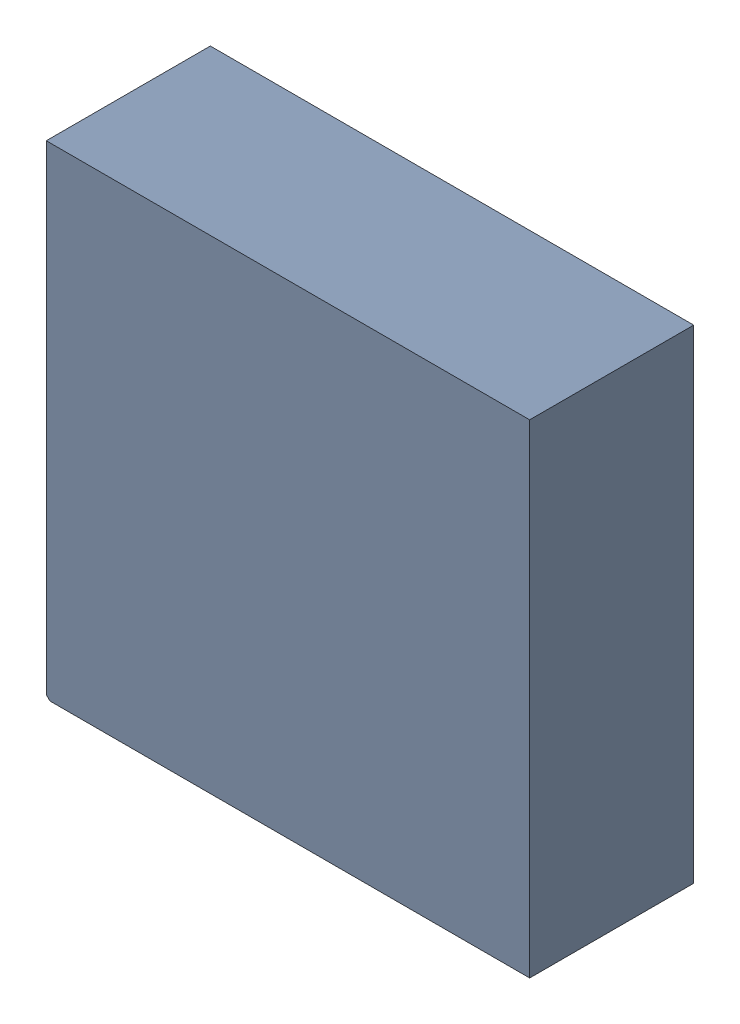
SolidWorks assembly U22, configuration ﾃﾞﾌｫﾙﾄ. Lengths in mm.
Overall size (3.3 3.3 1.12).
2 component instances, 1 part files, 0 mates.
Components (placement in the parent):
- 689262736-1: 689262736 [ﾃﾞﾌｫﾙﾄ] at (39 74 0) size (3.3 3.3 1.12)
  - Extruded_42-1: Extruded_42 [ﾃﾞﾌｫﾙﾄ] at origin size (3.3 3.3 1.12)
